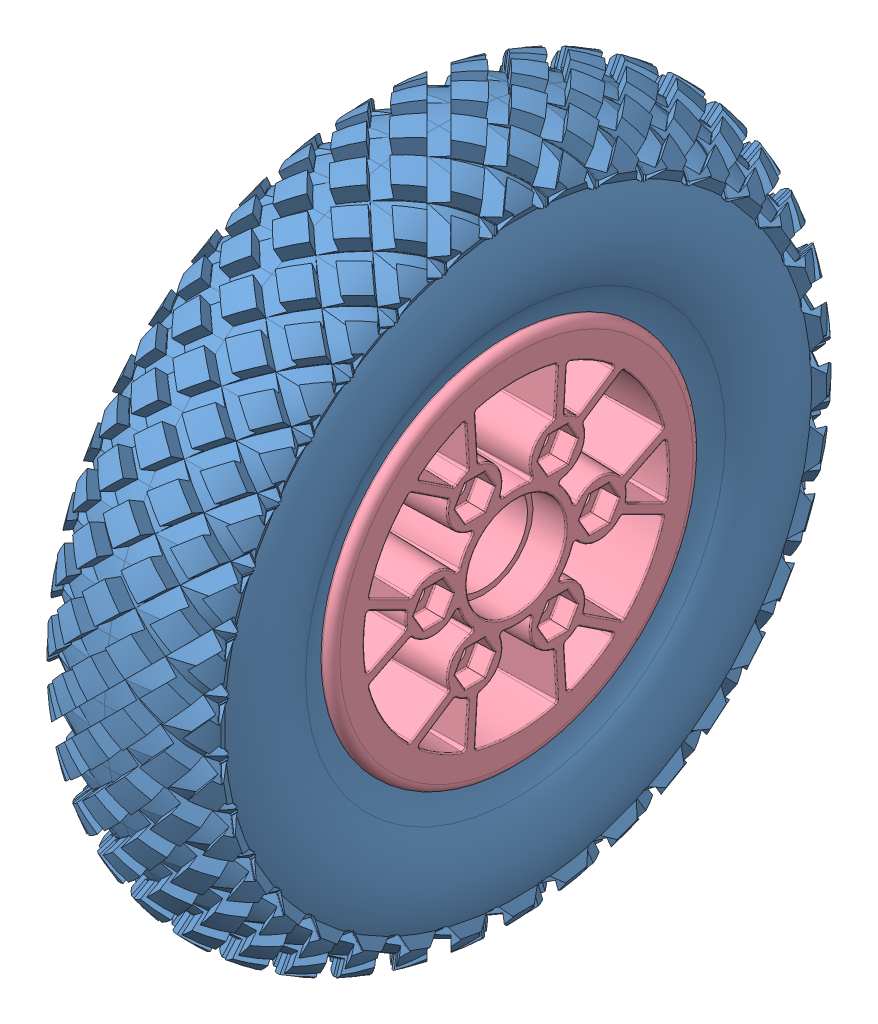
SolidWorks assembly 8in. Pneumatic Wheel, configuration Default. Lengths in mm.
Overall size (54.46 203.4 203.4).
11 component instances, 4 part files, 0 mates.
Components (placement in the parent):
- Tire-1: Tire [Default] at (-14.0642 3.9407 4.9955) x (0 0 1) z (-1 0 0) size (203.4 203.4 50.81)
- Valve-1: Valve [Default] at (-14.5404 48.2951 4.9955) x (0 1 0) z (0 0 1) size (16.51 34.98 12.8)
- Pneumatic Hub-1: Pneumatic Hub [Default] at (-8.6594 5.0758 -4.0835) size (45.47 106.55 106.55)
  - #4x1.00, Plastic Thread Rolling Screw, Pan Head, Cross Recessed, Zinc Plated (Plastic Applications)_-1: #4x1.00, Plastic Thread Rolling Screw, Pan Head, Cross Recessed, Zinc Plated (Plastic Applications)_ [Default] at (7.3269 34.0601 29.3991) x (-1 0 0) z (0 -0.924225 -0.381849) size (27.43 5.56 5.56)
  - Hub-1: Hub [Default] at (-28.6141 -1.1351 9.0791) size (25.79 106.55 106.55)
  - #4x1.00, Plastic Thread Rolling Screw, Pan Head, Cross Recessed, Zinc Plated (Plastic Applications)_-2: #4x1.00, Plastic Thread Rolling Screw, Pan Head, Cross Recessed, Zinc Plated (Plastic Applications)_ [Default] at (7.3269 -1.1351 -31.5609) x (-1 0 0) z (0 0.131421 0.991327) size (27.43 5.56 5.56)
  - #4x1.00, Plastic Thread Rolling Screw, Pan Head, Cross Recessed, Zinc Plated (Plastic Applications)_-3: #4x1.00, Plastic Thread Rolling Screw, Pan Head, Cross Recessed, Zinc Plated (Plastic Applications)_ [Default] at (-19.0891 -1.1351 49.7191) x (1 0 0) z (0 -0.750107 0.661316) size (27.43 5.56 5.56)
  - #4x1.00, Plastic Thread Rolling Screw, Pan Head, Cross Recessed, Zinc Plated (Plastic Applications)_-4: #4x1.00, Plastic Thread Rolling Screw, Pan Head, Cross Recessed, Zinc Plated (Plastic Applications)_ [Default] at (7.3269 -36.3304 29.3991) x (-1 0 0) z (0 0.792804 -0.609477) size (27.43 5.56 5.56)
  - #4x1.00, Plastic Thread Rolling Screw, Pan Head, Cross Recessed, Zinc Plated (Plastic Applications)_-5: #4x1.00, Plastic Thread Rolling Screw, Pan Head, Cross Recessed, Zinc Plated (Plastic Applications)_ [Default] at (-19.0891 34.0601 -11.2409) x (1 0 0) z (0 0.94777 0.318954) size (27.43 5.56 5.56)
  - #4x1.00, Plastic Thread Rolling Screw, Pan Head, Cross Recessed, Zinc Plated (Plastic Applications)_-6: #4x1.00, Plastic Thread Rolling Screw, Pan Head, Cross Recessed, Zinc Plated (Plastic Applications)_ [Default] at (-19.0891 -36.3304 -11.2409) x (1 0 0) z (0 -0.197663 -0.98027) size (27.43 5.56 5.56)
  - Hub-2: Hub [Default] at (16.8519 -1.1351 9.0791) x (-1 0 0) z (0 0 -1) size (25.79 106.55 106.55)
